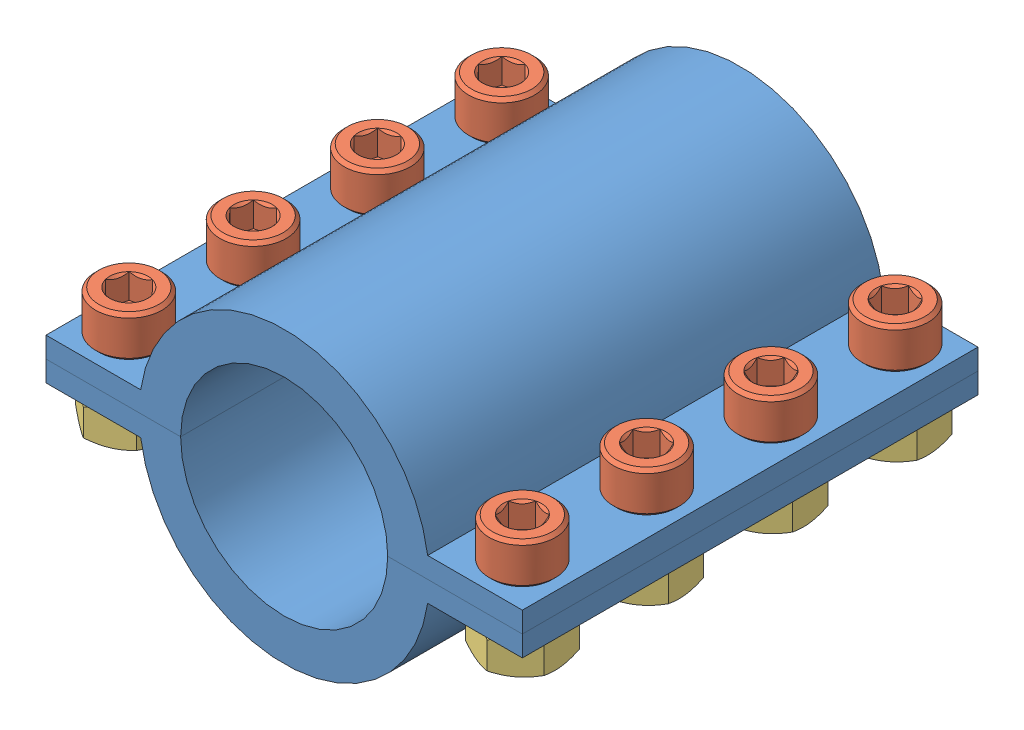
SolidWorks assembly hxr_assy, configuration Default. Lengths in mm.
Overall size (117.63 70 112.63).
18 component instances, 3 part files, 4 mates.
Components (placement in the parent):
- hxr_pipe-1: hxr_pipe [Default] at (-11.1123 -10.2223 -54.0806) size (115 35 110)
- hxr_pipe-2: hxr_pipe [Default] at (-11.1123 -10.2223 55.9194) x (1 0 0) z (0 0 -1) size (115 35 110)
- steel_bolt-1: steel_bolt [91292A157] at (36.3877 -25.2223 45.9194) x (-0.713383 0 -0.700774) z (0 -1 0) size (16 16 30.61)
- steel_hex_nut-1: steel_hex_nut [94223A103] at (36.3877 -19.2223 45.9194) x (-0.991828 0 0.127581) z (0 1 0) size (17 19.63 8)
- steel_hex_nut-2: steel_hex_nut [94223A103] at (36.3877 -19.2223 15.9194) x (-0.991828 0 0.127581) z (0 1 0) size (17 19.63 8)
- steel_hex_nut-3: steel_hex_nut [94223A103] at (36.3877 -19.2223 -14.0806) x (-0.991828 0 0.127581) z (0 1 0) size (17 19.63 8)
- steel_hex_nut-4: steel_hex_nut [94223A103] at (36.3877 -19.2223 -44.0806) x (-0.991828 0 0.127581) z (0 1 0) size (17 19.63 8)
- steel_bolt-2: steel_bolt [91292A157] at (36.3877 -25.2223 15.9194) x (-0.713383 0 -0.700774) z (0 -1 0) size (16 16 30.61)
- steel_bolt-3: steel_bolt [91292A157] at (36.3877 -25.2223 -14.0806) x (-0.713383 0 -0.700774) z (0 -1 0) size (16 16 30.61)
- steel_bolt-4: steel_bolt [91292A157] at (36.3877 -25.2223 -44.0806) x (-0.713383 0 -0.700774) z (0 -1 0) size (16 16 30.61)
- steel_hex_nut-5: steel_hex_nut [94223A103] at (-58.6123 -19.2223 45.9194) x (0.991828 0 0.127581) z (0 -1 0) size (17 19.63 8)
- steel_bolt-5: steel_bolt [91292A157] at (-58.6123 -25.2223 45.9194) x (-0.713383 0 0.700774) z (0 -1 0) size (16 16 30.61)
- steel_hex_nut-6: steel_hex_nut [94223A103] at (-58.6123 -19.2223 15.9194) x (0.991828 0 0.127581) z (0 -1 0) size (17 19.63 8)
- steel_hex_nut-7: steel_hex_nut [94223A103] at (-58.6123 -19.2223 -14.0806) x (0.991828 0 0.127581) z (0 -1 0) size (17 19.63 8)
- steel_hex_nut-8: steel_hex_nut [94223A103] at (-58.6123 -19.2223 -44.0806) x (0.991828 0 0.127581) z (0 -1 0) size (17 19.63 8)
- steel_bolt-6: steel_bolt [91292A157] at (-58.6123 -25.2223 15.9194) x (-0.713383 0 0.700774) z (0 -1 0) size (16 16 30.61)
- steel_bolt-7: steel_bolt [91292A157] at (-58.6123 -25.2223 -14.0806) x (-0.713383 0 0.700774) z (0 -1 0) size (16 16 30.61)
- steel_bolt-8: steel_bolt [91292A157] at (-58.6123 -25.2223 -44.0806) x (-0.713383 0 0.700774) z (0 -1 0) size (16 16 30.61)
Mates (geometry in assembly coordinates):
- Distance1: distance = 10 mm anti-aligned: plane of steel_bolt-1 through (36.3877 -5.2223 45.9194) normal (0 -1 0); plane of steel_hex_nut-1 through (45.4443 -15.2223 49.7024) normal (0 1 0)
- Coincident3: coincident anti-aligned: plane of hxr_pipe-1 through (46.3877 -5.2223 55.9194) normal (0 1 0); plane of steel_bolt-1 through (36.3877 -5.2223 45.9194) normal (0 -1 0)
- Concentric2: concentric anti-aligned: cylinder of hxr_pipe-1 through (36.3877 -115.2223 45.9194) axis (0 1 0) radius 5; cylinder of steel_bolt-1 through (36.3877 -5.2223 45.9194) axis (0 -1 0) radius 5
- Concentric3: concentric aligned: cylinder of steel_bolt-1 through (36.3877 -5.2223 45.9194) axis (0 -1 0) radius 5; cylinder of steel_hex_nut-1 through (36.3877 -15.2223 45.9194) axis (0 -1 0) radius 5
